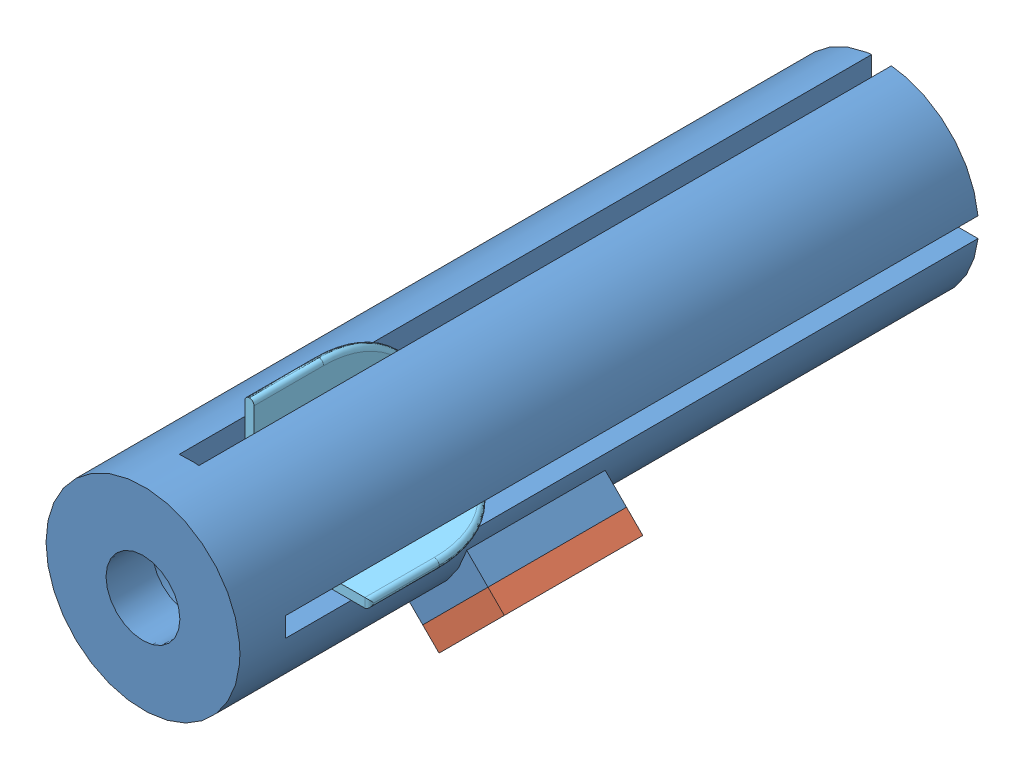
SolidWorks assembly MS-A-0015-FullReleaseMech, configuration Default. Lengths in mm.
Overall size (68.95 68.95 203.2).
5 component instances, 5 part files, 5 mates.
Components (placement in the parent):
- MS-P-ReleaseTube-001-1: MS-P-ReleaseTube-001 [Default] at (69.0922 -8.1199 122.4199) x (1 0 0) z (0 0 -1) size (58.1 58.1 203.2)
- MS-P-ElectroMagnetCover-1: MS-P-ElectroMagnetCover [Default] at (91.5429 -30.5706 39.8699) x (0 0 -1) z (0.707107 -0.707107 0) size (38.1 25.4 6.35)
- MS-P-001-SpiralProppeler-SelfMade-1: MS-P-001-SpiralProppeler-SelfMade [Default] at (69.0922 -8.1199 95.528) x (0.823895 -0.566743 0) z (0 0 1) size (29.55 29.55 11.64)
- MS-P-0041-AltNoseCone-1: MS-P-0041-AltNoseCone [Default] at (69.0922 -8.1199 -9.0574) x (0.049405 0.998779 0) z (-0.998779 0.049405 0) size (38.1 62.23 38.1)
- MS-P-0042-Torpedo_Body-1: MS-P-0042-Torpedo_Body [Default] at (69.0922 -8.1199 93.091) x (-0.001106 0.999999 0) z (0 0 -1) size (65.99 65.99 103.87)
Mates (geometry in assembly coordinates):
- Coincident5: coincident aligned: plane of MS-P-ReleaseTube-001-1 through (78.0725 0.8603 20.8199) normal (0.707107 0.707107 0); plane of MS-P-ElectroMagnetCover-1 through (105.0132 -26.0804 58.9199) normal (0.707107 0.707107 0)
- Coincident6: coincident aligned: plane of MS-P-ReleaseTube-001-1 through (69.0922 -8.1199 20.8199) normal (0 0 -1); plane of MS-P-ElectroMagnetCover-1 through (87.0527 -44.0409 20.8199) normal (0 0 -1)
- Concentric2: concentric anti-aligned: circle of MS-P-0041-AltNoseCone-1; circle of MS-P-0042-Torpedo_Body-1
- Concentric1: concentric anti-aligned: circle of MS-P-001-SpiralProppeler-SelfMade-1; circle of MS-P-0042-Torpedo_Body-1
- Concentric5: concentric aligned: circle of MS-P-ReleaseTube-001-1; circle of MS-P-0042-Torpedo_Body-1
